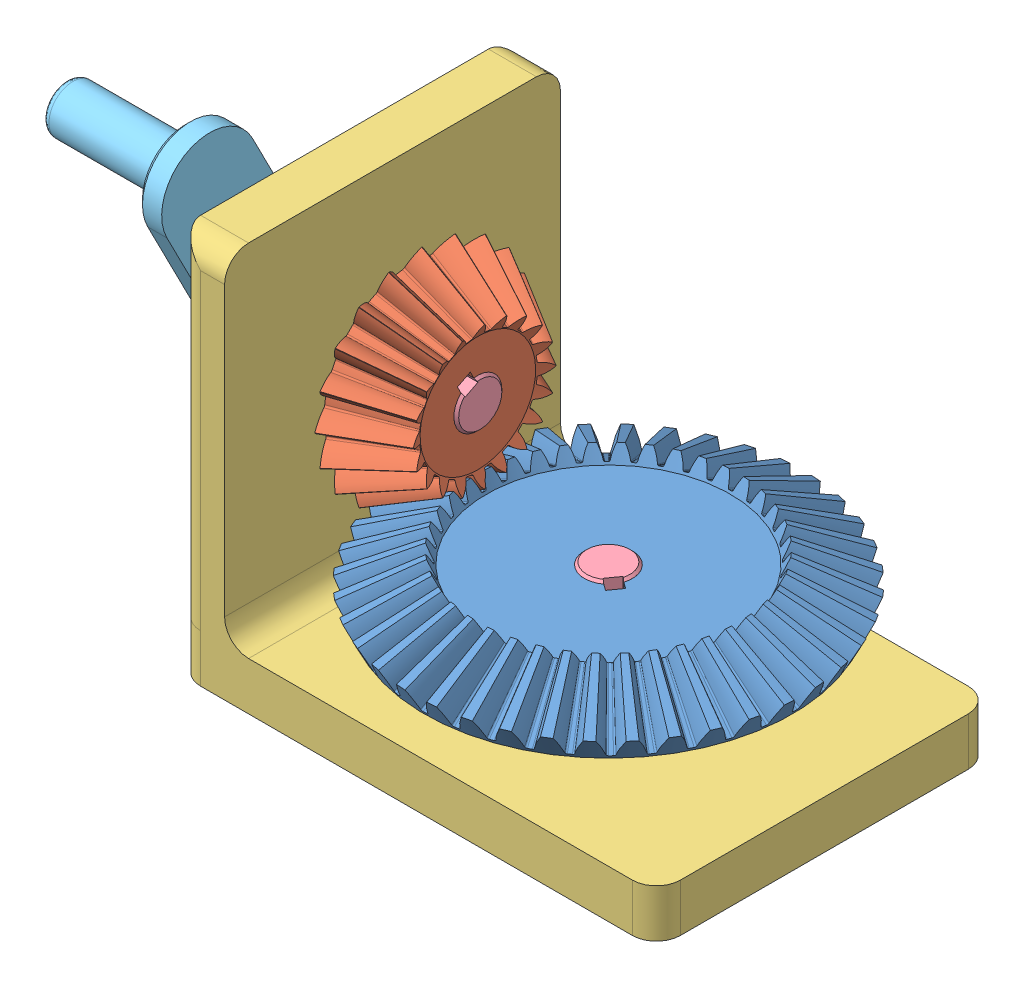
SolidWorks assembly KONİK DİŞLİ MEKANİZMA, configuration Default. Lengths in mm.
Overall size (316.62 201.56 226.4).
6 component instances, 5 part files, 17 mates.
Components (placement in the parent):
- straight bevel gear_am-2: straight bevel gear_am [Metric - Straight bevel gear 4M 40GT 20PT 20PA 30FW ---40O40H70MD20S1] x (0 1 0) z (0.57994 0 -0.814659) size (46.14 162.34 162.34)
- straight bevel pinion_am-2: straight bevel pinion_am [Metric - Straight bevel pinion 4M20PT 40GT 20PA 30FW ---20O40H90MD20S1] at (-81.8856 46.8569 0) x (1 0 0) z (0 -0.455856 0.890054) size (39.95 88.85 88.85)
- TABAN-1: TABAN [Default] at (90 -43.1431 70) x (-1 0 0) z (0 -1 0) size (200 140 160)
- ŞAFT-1: ŞAFT [Default] at (-153.4203 46.8569 0) x (0 0.455856 -0.890054) z (1 0 0) size (20 20 100)
- ŞAFT-2: ŞAFT [Default] at (0 -83.2837 0) x (-0.57994 0 0.814659) z (0 1 0) size (20 20 100)
- Çevirme Kolu-1: Çevirme Kolu [Default] at (-143.4203 46.8569 0) x (0 0.890054 0.455856) z (-1 0 0) size (90 40 60)
Mates (geometry in assembly coordinates):
- Coincident1: coincident anti-aligned: plane of straight bevel gear_am-2 through (0 0 0) normal (0 -1 0); plane of assembly through (0 0 0) normal (0 1 0)
- Concentric2: concentric: cylinder of straight bevel gear_am-2 through (0 70.0001 0) axis (0 -1 0) radius 10; point of assembly
- Coincident3: coincident: point of straight bevel gear_am-2; point of straight bevel pinion_am-2
- Perpendicular1: perpendicular: line of straight bevel gear_am-2 through (0 -10 0) axis (0 1 0); line of straight bevel pinion_am-2 through (-91.8856 46.8569 0) axis (1 0 0)
- Coincident5: coincident: line of straight bevel pinion_am-2 through (-91.8856 46.8569 0) axis (1 0 0); plane of assembly
- GearMate3: gear = 40 : 20 mm: circle of straight bevel pinion_am-2; circle of straight bevel gear_am-2
- Concentric3: concentric anti-aligned: cylinder of straight bevel gear_am-2 through (0 70.0001 0) axis (0 -1 0) radius 10; cylinder of TABAN-1 through (0 -43.1431 0) axis (0 1 0) radius 10
- Coincident6: coincident anti-aligned: plane of straight bevel gear_am-2 through (0 -23.1432 0) normal (0 -1 0); plane of TABAN-1 through (-100 -23.1431 60) normal (0 1 0)
- Concentric4: concentric anti-aligned: cylinder of straight bevel pinion_am-2 through (8.1145 46.8569 0) axis (-1 0 0) radius 10; cylinder of TABAN-1 through (-110 46.8569 0) axis (1 0 0) radius 10
- Concentric5: concentric anti-aligned: cylinder of TABAN-1 through (-110 46.8569 0) axis (1 0 0) radius 10; cylinder of ŞAFT-1 through (-53.4203 46.8569 0) axis (-1 0 0) radius 10
- Coincident8: coincident anti-aligned: circle of straight bevel pinion_am-2; circle of ŞAFT-1
- Parallel2: parallel anti-aligned: line of ŞAFT-1 through (-53.4203 52.6098 6.317) axis (0 0.455856 -0.890054); line of straight bevel pinion_am-2 through (-54.4203 59.6172 3.1648) axis (0 -0.455856 0.890054)
- Coincident10: coincident anti-aligned: circle of straight bevel gear_am-2; circle of ŞAFT-2
- Parallel3: parallel anti-aligned: plane of straight bevel gear_am-2 through (12.1675 70.0001 4.9793) normal (-0.814659 0 -0.57994); plane of ŞAFT-2 through (8.2571 -13.2837 2.1955) normal (0.814659 0 0.57994)
- Concentric6: concentric anti-aligned: cylinder of ŞAFT-1 through (-53.4203 46.8569 0) axis (-1 0 0) radius 10; cylinder of Çevirme Kolu-1 through (-153.4203 46.8569 0) axis (1 0 0) radius 10
- Coincident12: coincident aligned: plane of ŞAFT-1 through (-153.4203 46.8569 0) normal (-1 0 0); plane of Çevirme Kolu-1 through (-153.4203 46.8569 0) normal (-1 0 0)
- Parallel4: parallel anti-aligned: plane of ŞAFT-1 through (-133.4203 55.3449 0.9767) normal (0 0.890054 0.455856); plane of Çevirme Kolu-1 through (-153.4203 58.9051 2.8001) normal (0 -0.890054 -0.455856)
